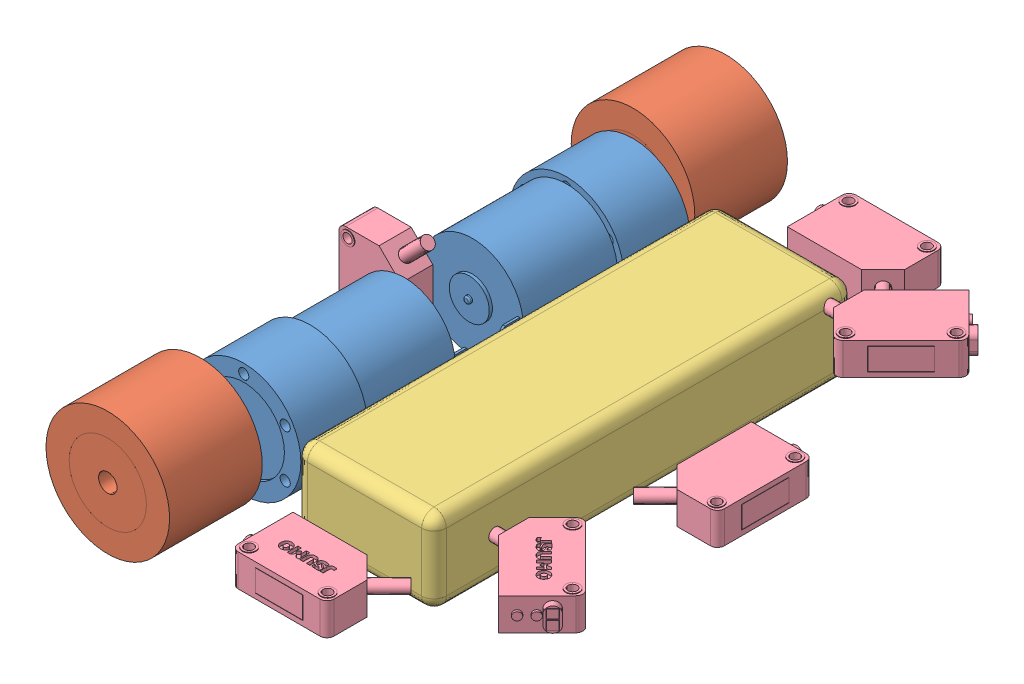
SolidWorks assembly ensamblaje2, configuration Predeterminado. Lengths in mm.
Overall size (200 40.49 200).
13 component instances, 4 part files, 7 mates.
Components (placement in the parent):
- Motor+Rueda-4: Motor+Rueda [Predeterminado] at (66.5149 60.1975 66.5157) x (-1 0 0) z (0 0 -1) size (40 40 170.38)
  - Titan-37mm-500rpm-2: Titan-37mm-500rpm [Predeterminado] at (-8.182 1.2078 75.625) x (0 1 0) z (0 0 1) size (37 37 78.75)
  - js4030-wheel-cad-1: js4030-wheel-cad [Predeterminado] at (-21.4262 1.7536 159.125) x (-1 0 0) z (0 0 -1) size (40 40 30)
- Motor+Rueda-6: Motor+Rueda [Predeterminado] at (66.5149 62.6131 -1.7343) x (-1 0 0) z (0 0 1) size (40 40 170.38)
  - Titan-37mm-500rpm-2: Titan-37mm-500rpm [Predeterminado] at (-8.182 1.2078 75.625) x (0 1 0) z (0 0 1) size (37 37 78.75)
  - js4030-wheel-cad-1: js4030-wheel-cad [Predeterminado] at (-21.4262 1.7536 159.125) x (-1 0 0) z (0 0 -1) size (40 40 30)
- Bateria-4: Bateria [Predeterminado] at (118.7811 44.4076 32.3907) x (0 0 -1) z (1 0 0) size (136 27 45)
- OMRON-E3Z-D62_D82-1: OMRON-E3Z-D62_D82 [Predeterminado] at (50.6947 74.1053 32.3907) x (1 0 0) z (0 0 -1) size (24.99 38.09 10.8)
- OMRON-E3Z-D62_D82-2: OMRON-E3Z-D62_D82 [Predeterminado] at (135.8447 57.9076 129.3907) x (0 0 -1) z (0 1 0) size (24.99 38.09 10.8)
- OMRON-E3Z-D62_D82-3: OMRON-E3Z-D62_D82 [Predeterminado] at (135.8447 57.9076 -64.6093) x (0 0 1) z (0 -1 0) size (24.99 38.09 10.8)
- OMRON-E3Z-D62_D82-4: OMRON-E3Z-D62_D82 [Predeterminado] at (173.4996 57.9076 41.0762) x (-1 0 0) z (0 -1 0) size (24.99 38.09 10.8)
- OMRON-E3Z-D62_D82-5: OMRON-E3Z-D62_D82 [Predeterminado] at (156.3973 57.9076 70.6456) x (-0.707107 0 0.707107) z (0 1 0) size (24.99 38.09 10.8)
- OMRON-E3Z-D62_D82-6: OMRON-E3Z-D62_D82 [Predeterminado] at (156.3464 67.4076 -17.7762) x (-0.707107 0 -0.707107) z (0 -1 0) size (24.99 38.09 10.8)
Mates (geometry in assembly coordinates):
- Concéntrica4: concentric anti-aligned: cylinder of Motor+Rueda-4/js4030-wheel-cad-1 through (67.6947 61.4053 -37.6093) axis (0 0 -1) radius 20; cylinder of Motor+Rueda-6/js4030-wheel-cad-1 through (67.6947 61.4053 102.3907) axis (0 0 1) radius 20
- Distancia4: distance = 200 mm anti-aligned: plane of Motor+Rueda-6/js4030-wheel-cad-1 through (67.6947 61.4053 132.3907) normal (0 0 1); plane of Motor+Rueda-4/js4030-wheel-cad-1 through (67.6947 61.4053 -67.6093) normal (0 0 -1)
- Ancho4: width aligned: plane of OMRON-E3Z-D62_D82-1 through (47.6947 76.9053 37.5907) normal (0 1 0); plane of OMRON-E3Z-D62_D82-1 through (67.6947 45.9053 37.5907) normal (0 -1 0); plane of Motor+Rueda-4/Titan-37mm-500rpm-2 through (60.072 63.3512 21.3907) normal (0 1 0); plane of Motor+Rueda-4/Titan-37mm-500rpm-2 through (59.322 59.4594 21.3907) normal (0 -1 0)
- Ancho5: width aligned: plane of OMRON-E3Z-D62_D82-1 through (50.6947 74.1053 37.5907) normal (0 0 1); plane of OMRON-E3Z-D62_D82-1 through (50.6947 74.1053 27.1907) normal (0 0 -1); plane of Motor+Rueda-4/js4030-wheel-cad-1 through (67.6947 61.4053 -67.6093) normal (0 0 1); plane of Motor+Rueda-6/js4030-wheel-cad-1 through (67.6947 61.4053 132.3907) normal (0 0 -1)
- Coincidente1: coincident: plane of OMRON-E3Z-D62_D82-1 through (47.6947 45.9053 37.5907) normal (-1 0 0); line of assembly
- Coincidente5: coincident aligned: plane of OMRON-E3Z-D62_D82-2 through (135.8447 63.1076 129.3907) normal (0 1 0); plane of OMRON-E3Z-D62_D82-3 through (135.8447 63.1076 -64.6093) normal (0 1 0)
- Coincidente6: coincident aligned: plane of OMRON-E3Z-D62_D82-2 through (107.6447 52.7076 112.3907) normal (-1 0 0); plane of OMRON-E3Z-D62_D82-3 through (107.6447 63.1076 -47.6093) normal (-1 0 0)
